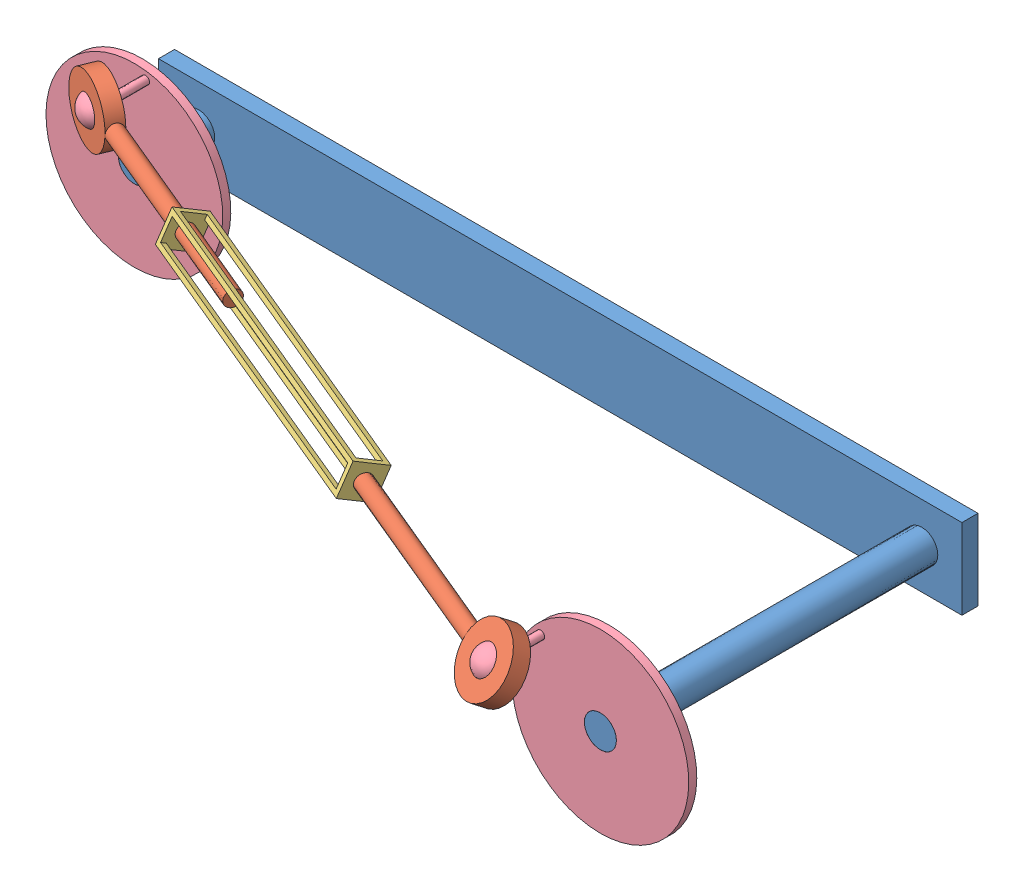
SolidWorks assembly Złożenie1, configuration Domyślna. Lengths in mm.
Overall size (589.78 158.69 261.23).
6 component instances, 4 part files, 8 mates.
Components (placement in the parent):
- Base-1: Base [Default] at (-277.1858 1.6475 395) size (500 50 210)
- Connecting_Rod-1: Connecting_Rod [Default] at (-245.241 76.1628 475) x (0.929689 -0.036854 0.366497) z (-0.366336 0.011278 0.930414) size (170 40 10)
- Connector_Block-1: Connector_Block [Default] at (-162.4315 67.3026 521.7014) x (0.929689 -0.036854 0.366497) z (0.172727 0.922424 -0.345397) size (200 20 20)
- Wheel_component-1: Wheel_component [Default] at (-245.241 76.1628 475) x (0 0 -1) z (0.990307 -0.138897 0) size (45 115 110)
- Wheel_component-2: Wheel_component [Default] at (160.6294 60.0735 635) x (0 0 -1) z (0.668519 0.743695 0) size (45 115 110)
- Connecting_Rod-2: Connecting_Rod [Default] at (160.6294 60.0735 635) x (-0.929689 0.036854 -0.366497) z (-0.28797 0.547687 0.785565) size (170 40 10)
Mates (geometry in assembly coordinates):
- Koncentryczne1: concentric anti-aligned: circle of Base-1; circle of Wheel_component-1
- Wspólnie2: coincident anti-aligned: circle of Base-1; circle of Wheel_component-1
- Koncentryczne2: concentric anti-aligned: circle of Base-1; circle of Wheel_component-2
- Wspólnie4: coincident anti-aligned: circle of Base-1; circle of Wheel_component-2
- Koncentryczne3: concentric: sphere of Connecting_Rod-1; sphere of Wheel_component-1
- Koncentryczne4: concentric anti-aligned: cylinder of Connecting_Rod-1 through (-245.241 76.1628 475) axis (-0.929689 0.036854 -0.366497) radius 5; cylinder of Connector_Block-1 through (-157.4509 72.6827 509.6081) axis (0.929689 -0.036854 0.366497) radius 5
- Koncentryczne7: concentric: sphere of Wheel_component-2; sphere of Connecting_Rod-2
- Koncentryczne8: concentric aligned: cylinder of Connector_Block-1 through (-157.4509 72.6827 509.6081) axis (0.929689 -0.036854 0.366497) radius 5; cylinder of Connecting_Rod-2 through (160.6294 60.0735 635) axis (0.929689 -0.036854 0.366497) radius 5
